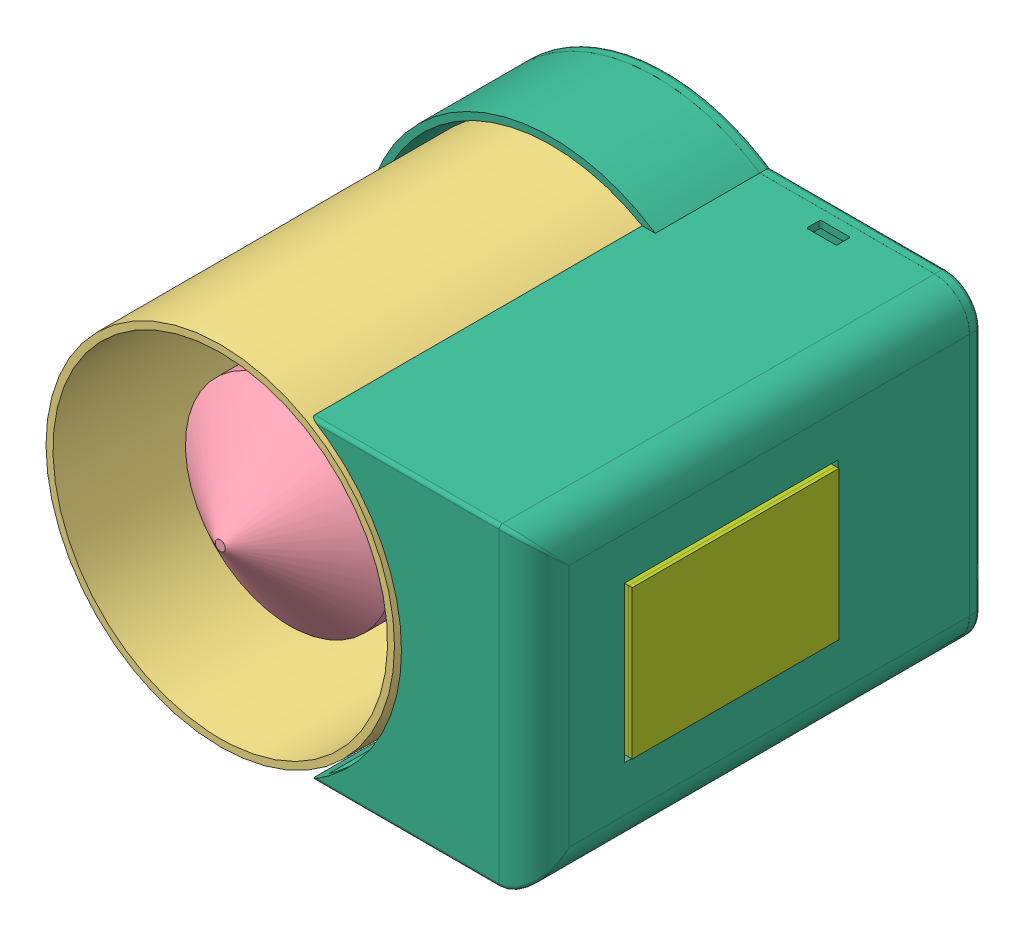
SolidWorks assembly Assembly Atas, configuration Default. Lengths in mm.
Overall size (145.2 108 128).
20 component instances, 16 part files, 36 mates.
Components (placement in the parent):
- Load Cell-1: Load Cell [Default] at (8.9865 39.3744 74.0353) size (80 13 13)
- Ganjal atas-1: Ganjal atas [Default] at (-6.4926 45.8744 73.4815) x (1 0 0) z (0 -1 0) size (25 5 13)
- Elektroda luar-1: Elektroda luar [Default] at (-6.4926 45.8744 78.4815) x (1 0 0) z (0 -1 0) size (100 102 100)
- Elektroda dalam-1: Elektroda dalam [Default] at (-6.4926 45.8744 80.4815) x (1 0 0) z (0 -1 0) size (74 100 74)
- Ds Sensor-1: Ds Sensor [Default] at (-6.4926 10.8744 87.2056) x (-0.463346 -0.886177 0) z (-0.886177 0.463346 0) size (7 71 7.01)
- Ganjal atas-2: Ganjal atas [Default] at (48.5074 45.8744 55.4815) x (1 0 0) z (0 -1 0) size (25 5 13)
- Alas Bawah-1: Alas Bawah [Default] at (18.5074 45.8744 52.4815) x (1 0 0) z (0 -1 0) size (144 128 108)
- 2.4in TFT Screen (SPFD5408)-1: 2.4in TFT Screen (SPFD5408) [Default] at (79.9074 45.8744 124.3815) x (0 0 -1) z (0 -1 0) size (72.2 6.8 52.9)
- 3.7v li-ion 500mah Battery-1: 3.7v li-ion 500mah Battery [Default] at (83.8162 45.6244 66.1815) x (0 0 1) z (0 -1 0) size (49.65 6.07 37.83)
  - 3.7v li-ion 500mah Battery.step-1: 3.7v li-ion 500mah Battery.step [Default] at origin size (49.65 6.07 37.83)
    - 3.7v li-ion 500mah Battery1.step-1: 3.7v li-ion 500mah Battery1.step [Default] at origin size (24.5 6.02 35.83)
    - 3.7v li-ion 500mah Battery2.step-1: 3.7v li-ion 500mah Battery2.step [Default] at origin size (32.9 1.72 9.13)
    - 3.7v li-ion 500mah Battery3.step-1: 3.7v li-ion 500mah Battery3.step [Default] at origin size (33.79 2.66 8.16)
    - 3.7v li-ion 500mah Battery4.step-1: 3.7v li-ion 500mah Battery4.step [Default] at origin size (32.1 1.24 10.32)
    - 3.7v li-ion 500mah Battery5.step-1: 3.7v li-ion 500mah Battery5.step [Default] at origin size (4.96 3.45 6)
    - 3.7v li-ion 500mah Battery6.step-1: 3.7v li-ion 500mah Battery6.step [Default] at origin size (23.97 5.89 35.28)
- ARDUINO UNO R3-1: ARDUINO UNO R3 [Default] at (68.5074 46.0044 123.5128) x (0 0 1) z (1 0 0) size (75.3 52.08 13.9)
- ARDUINO UNO R3-2: ARDUINO UNO R3 [Default] at (57.1074 46.0044 123.5128) x (0 0 1) z (1 0 0) size (75.3 52.08 13.9)
- Charger module_TC4056A_5V1A_USB Micro-1: Charger module_TC4056A_5V1A_USB Micro [Default] at (48.0074 72.8744 59.4815) size (17 28.59 3.68)
- DudukanBoard-1: DudukanBoard [Default] at (57.1074 46.0044 123.5128) x (0 0 -1) z (-1 0 0) size (62.8 70 7)
Mates (geometry in assembly coordinates):
- Concentric1: concentric anti-aligned: cylinder of Load Cell-1 through (1.0074 45.8744 73.4815) axis (0 0 1) radius 2; cylinder of Ganjal atas-1 through (1.0074 45.8744 78.4815) axis (0 0 -1) radius 2
- Concentric2: concentric aligned: cylinder of Load Cell-1 through (-13.9926 45.8744 60.4815) axis (0 0 -1) radius 2; cylinder of Ganjal atas-1 through (-13.9926 45.8744 78.4815) axis (0 0 -1) radius 2
- Coincident1: coincident anti-aligned: plane of Load Cell-1 through (61.0074 52.3744 73.4815) normal (0 0 1); plane of Ganjal atas-1 through (-6.4926 45.8744 73.4815) normal (0 0 -1)
- Concentric3: concentric anti-aligned: cylinder of Ganjal atas-1 through (-13.9926 45.8744 78.4815) axis (0 0 -1) radius 2; cylinder of Elektroda luar-1 through (-13.9926 45.8744 72.8246) axis (0 0 1) radius 2
- Concentric4: concentric anti-aligned: cylinder of Ganjal atas-1 through (1.0074 45.8744 78.4815) axis (0 0 -1) radius 2; cylinder of Elektroda luar-1 through (1.0074 45.8744 72.8246) axis (0 0 1) radius 2
- Coincident2: coincident anti-aligned: plane of Ganjal atas-1 through (-6.4926 45.8744 78.4815) normal (0 0 1); plane of Elektroda luar-1 through (-6.4926 45.8744 78.4815) normal (0 0 -1)
- Concentric5: concentric anti-aligned: cylinder of Elektroda luar-1 through (-6.4926 10.8744 75.4815) axis (0 0 1) radius 3.5; cylinder of Ds Sensor-1 through (-6.4926 10.8744 102.2056) axis (0 0 -1) radius 3.5
- Coincident3: coincident aligned: plane of Elektroda luar-1 through (-6.4926 45.8744 80.4815) normal (0 0 1); plane of Ds Sensor-1 through (-6.4926 10.8744 80.4815) normal (0 0 1)
- Coincident4: coincident: plane of Elektroda luar-1 through (-6.4926 45.8744 100.4815) normal (0 0 1); plane of Elektroda dalam-1 through (-6.4926 45.8744 100.4815) normal (0 0 -1)
- Concentric6: concentric: cylinder of Elektroda luar-1 through (-6.4926 45.8744 100.4815) axis (0 0 -1) radius 2; cylinder of Elektroda dalam-1 through (-6.4926 45.8744 100.4815) axis (0 0 -1) radius 2
- Concentric7: concentric anti-aligned: cylinder of Load Cell-1 through (41.0074 45.8744 73.4815) axis (0 0 1) radius 2.5; cylinder of Ganjal atas-2 through (41.0074 45.8744 60.4815) axis (0 0 -1) radius 2
- Concentric8: concentric anti-aligned: cylinder of Load Cell-1 through (56.0074 45.8744 73.4815) axis (0 0 1) radius 2.5; cylinder of Ganjal atas-2 through (56.0074 45.8744 60.4815) axis (0 0 -1) radius 2
- Coincident5: coincident anti-aligned: plane of Load Cell-1 through (-18.9926 52.3744 60.4815) normal (0 0 -1); plane of Ganjal atas-2 through (48.5074 45.8744 60.4815) normal (0 0 1)
- Concentric10: concentric anti-aligned: cylinder of Ganjal atas-2 through (41.0074 45.8744 60.4815) axis (0 0 -1) radius 2; cylinder of Alas Bawah-1 through (41.0074 45.8744 50.4815) axis (0 0 1) radius 2
- Concentric9: concentric anti-aligned: cylinder of Ganjal atas-2 through (56.0074 45.8744 60.4815) axis (0 0 -1) radius 2; cylinder of Alas Bawah-1 through (56.0074 45.8744 50.4815) axis (0 0 1) radius 2
- Coincident7: coincident anti-aligned: plane of Ganjal atas-2 through (48.5074 45.8744 55.4815) normal (0 0 -1); plane of Alas Bawah-1 through (18.5074 45.8744 55.4815) normal (0 0 1)
- Coincident8: coincident anti-aligned: plane of Alas Bawah-1 through (81.5074 45.8744 55.4815) normal (-1 0 0); plane of 2.4in TFT Screen (SPFD5408)-1 through (81.5074 45.8744 124.3815) normal (1 0 0)
- Distance1: distance = 20 mm aligned: plane of 2.4in TFT Screen (SPFD5408)-1 through (81.5074 19.4244 160.4815) normal (0 0 1); plane of Alas Bawah-1 through (-6.4926 45.8744 180.4815) normal (0 0 1)
- Width1: width aligned: plane of 2.4in TFT Screen (SPFD5408)-1 through (81.5074 72.3244 160.4815) normal (0 1 0); plane of 2.4in TFT Screen (SPFD5408)-1 through (81.5074 19.4244 160.4815) normal (0 -1 0); plane of Alas Bawah-1 through (18.5074 90.8744 55.4815) normal (0 1 0); plane of Alas Bawah-1 through (18.5074 0.8744 55.4815) normal (0 -1 0)
- Coincident10: coincident anti-aligned: plane of Alas Bawah-1 through (81.5074 45.8744 55.4815) normal (-1 0 0); plane of 3.7v li-ion 500mah Battery-1/3.7v li-ion 500mah Battery.step-1/3.7v li-ion 500mah Battery6.step-1 through (81.5074 45.6244 57.1809) normal (1 0 0)
- Parallel1: parallel: plane of Alas Bawah-1 through (18.5074 45.8744 55.4815) normal (0 0 1); line of 3.7v li-ion 500mah Battery-1/3.7v li-ion 500mah Battery.step-1/3.7v li-ion 500mah Battery1.step-1 through (75.4562 61.6244 56.9815) axis (0 -1 0)
- Distance2: distance = 1.5 mm: line of 3.7v li-ion 500mah Battery-1/3.7v li-ion 500mah Battery.step-1/3.7v li-ion 500mah Battery1.step-1 through (75.4562 61.6244 56.9815) axis (0 -1 0); plane of Alas Bawah-1 through (18.5074 45.8744 55.4815) normal (0 0 1)
- Width2: width anti-aligned: plane of 3.7v li-ion 500mah Battery-1/3.7v li-ion 500mah Battery.step-1/3.7v li-ion 500mah Battery1.step-1 through (78.4562 63.6244 66.1815) normal (0 1 0); plane of Alas Bawah-1 through (78.4562 28.1244 66.1815) normal (0 -1 0); plane of 3.7v li-ion 500mah Battery-1/3.7v li-ion 500mah Battery.step-1/3.7v li-ion 500mah Battery6.step-1 through (18.5074 0.8744 55.4815) normal (0 -1 0); plane of Alas Bawah-1 through (18.5074 90.8744 55.4815) normal (0 1 0)
- Coincident14: coincident anti-aligned: plane of 2.4in TFT Screen (SPFD5408)-1 through (79.9074 45.8744 124.3815) normal (-1 0 0); plane of ARDUINO UNO R3-1 through (79.9074 46.0044 123.5128) normal (1 0 0)
- Concentric11: concentric aligned: circle of 2.4in TFT Screen (SPFD5408)-1; circle of ARDUINO UNO R3-1
- Parallel3: parallel aligned: plane of 2.4in TFT Screen (SPFD5408)-1 through (81.5074 19.4244 160.4815) normal (0 -1 0); plane of ARDUINO UNO R3-1 through (69.9074 19.9644 91.3128) normal (0 -1 0)
- Coincident17: coincident anti-aligned: plane of ARDUINO UNO R3-1 through (68.5074 20.7644 91.3128) normal (-1 0 0); plane of ARDUINO UNO R3-2 through (68.5074 46.0044 123.5128) normal (1 0 0)
- Concentric15: concentric aligned: cylinder of ARDUINO UNO R3-1 through (69.9074 37.6644 156.5128) axis (-1 0 0) radius 1.6; cylinder of ARDUINO UNO R3-2 through (58.5074 37.6644 156.5128) axis (-1 0 0) radius 1.6
- Concentric16: concentric aligned: cylinder of ARDUINO UNO R3-1 through (69.9074 69.5444 105.7128) axis (-1 0 0) radius 1.6; cylinder of ARDUINO UNO R3-2 through (58.5074 69.5444 105.7128) axis (-1 0 0) radius 1.6
- Distance3: distance = 3 mm anti-aligned: plane of Charger module_TC4056A_5V1A_USB Micro-1 through (48.0074 72.8744 58.4815) normal (0 0 -1); plane of Alas Bawah-1 through (18.5074 45.8744 55.4815) normal (0 0 1)
- Distance5: distance = 2 mm anti-aligned: plane of Alas Bawah-1 through (18.5074 88.8744 55.4815) normal (0 -1 0); plane of Charger module_TC4056A_5V1A_USB Micro-1 through (54.0074 86.8744 59.4815) normal (0 1 0)
- Distance4: distance = 25 mm anti-aligned: plane of Charger module_TC4056A_5V1A_USB Micro-1 through (56.5074 86.8744 59.4815) normal (1 0 0); plane of Alas Bawah-1 through (81.5074 45.8744 55.4815) normal (-1 0 0)
- InPlace1: in place: plane of ARDUINO UNO R3-2 through (57.1074 20.7644 91.3128) normal (-1 0 0); plane of ? through (57.1074 0 0) normal (-1 0 0); moOrthogonalPlaneRef_w of ARDUINO UNO R3-2 through (57.1074 20.7644 91.3128) normal (-1 0 0); plane of ? through (57.1074 0 0) normal (0 1 0); plane of ARDUINO UNO R3-2 through (57.1074 20.7644 91.3128) normal (-1 0 0); plane of ? through (57.1074 0 0) normal (0 0 1); plane of ARDUINO UNO R3-2 through (57.1074 20.7644 91.3128) normal (-1 0 0); unknown of DudukanBoard-1
- Coincident21: coincident aligned: plane of ARDUINO UNO R3-2; plane of DudukanBoard-1
- Coincident22: coincident aligned: moOrthogonalPlaneRef_w of ARDUINO UNO R3-2 through (57.1074 46.0044 123.5128) normal (0 -1 0); plane of DudukanBoard-1 through (57.1074 46.0044 123.5128) normal (0 -1 0)
- Coincident23: coincident anti-aligned: moOrthogonalPlaneRef_w of ARDUINO UNO R3-2 through (57.1074 46.0044 123.5128) normal (0 0 1); plane of DudukanBoard-1 through (57.1074 46.0044 123.5128) normal (0 0 -1)
